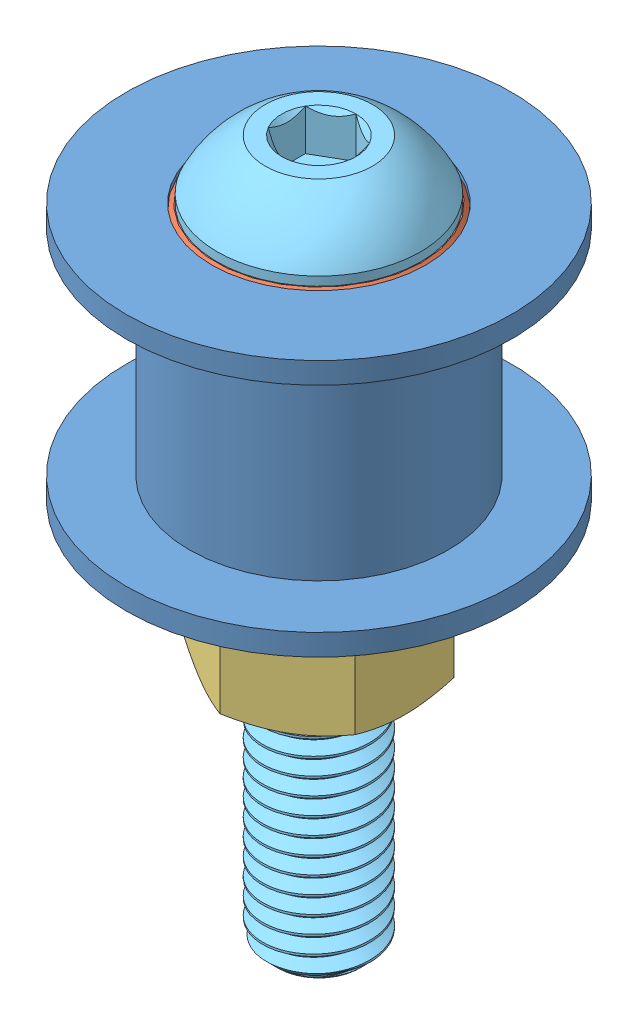
SolidWorks assembly 20T Idler Pulley wBearing, configuration Default. Lengths in mm.
Overall size (18 33.32 18).
6 component instances, 5 part files, 9 mates.
Components (placement in the parent):
- Powge 20T Idler Pulley-1: Powge 20T Idler Pulley [Default] at origin size (18 12 18)
- 7804K106_STAINLESS STEEL BALL BEARING-1: 7804K106_STAINLESS STEEL BALL BEARING [7804K106] at (0 4 0) x (1 0 0) z (0 -1 0) size (10 10 4)
- 7804K106_STAINLESS STEEL BALL BEARING-2: 7804K106_STAINLESS STEEL BALL BEARING [7804K106] at (0 -4 0) x (-1 0 0) z (0 1 0) size (10 10 4)
- 90591A146_M5 ZINC PLATED STEEL HEX NUT-1: 90591A146_M5 ZINC PLATED STEEL HEX NUT [90591A146] at (0 -10.7 0) x (1 0 0) z (0 1 0) size (8 9.24 4.46)
- 90695A037_M5 CLASS 04 STEEL THIN HEX NUT - DIN 439B-1: 90695A037_M5 CLASS 04 STEEL THIN HEX NUT - DIN 439B [90695A037] at (0 -7.35 0) size (8 3.32 9.24)
- 91239A236_M5x30 CLASS 10.9 STL BUTTON-HEAD SOCKET CAP SCREW-1: 91239A236_M5x30 CLASS 10.9 STL BUTTON-HEAD SOCKET CAP SCREW [91239A236] at (0 8.75 0) x (1 0 0) z (0 1 0) size (9.5 9.5 33.32)
Mates (geometry in assembly coordinates):
- Coincident1: coincident anti-aligned: plane of Powge 20T Idler Pulley-1 through (-5 2 0) normal (0 1 0); plane of 7804K106_STAINLESS STEEL BALL BEARING-1 through (0 2 4.8) normal (0 -1 0)
- Concentric1: concentric anti-aligned: cylinder of Powge 20T Idler Pulley-1 through (0 6 0) axis (0 1 0) radius 5; cylinder of 7804K106_STAINLESS STEEL BALL BEARING-1 through (0 2 0) axis (0 -1 0) radius 5
- Coincident2: coincident anti-aligned: plane of 90591A146_M5 ZINC PLATED STEEL HEX NUT-1 through (-4 -8.7 -2.3094) normal (0 1 0); plane of 90695A037_M5 CLASS 04 STEEL THIN HEX NUT - DIN 439B-1 through (-4 -8.7 -2.3094) normal (0 -1 0)
- Coincident3: coincident aligned: plane of 90591A146_M5 ZINC PLATED STEEL HEX NUT-1 through (0 -8.7 4.6188) normal (0.5 0 0.866025); plane of 90695A037_M5 CLASS 04 STEEL THIN HEX NUT - DIN 439B-1 through (0 -6 4.6188) normal (0.5 0 0.866025)
- Concentric2: concentric aligned: circle of 90591A146_M5 ZINC PLATED STEEL HEX NUT-1; circle of 90695A037_M5 CLASS 04 STEEL THIN HEX NUT - DIN 439B-1
- Coincident5: coincident anti-aligned: plane of 7804K106_STAINLESS STEEL BALL BEARING-2 through (0 -6 2.7) normal (0 -1 0); plane of 90695A037_M5 CLASS 04 STEEL THIN HEX NUT - DIN 439B-1 through (-4 -6 -2.3094) normal (0 1 0)
- Coincident6: coincident anti-aligned: cylinder of 7804K106_STAINLESS STEEL BALL BEARING-2 through (0 -2 0) axis (0 1 0) radius 2.5; circle of 90591A146_M5 ZINC PLATED STEEL HEX NUT-1
- Coincident7: coincident anti-aligned: plane of 7804K106_STAINLESS STEEL BALL BEARING-1 through (0 6 2.7) normal (0 1 0); plane of 91239A236_M5x30 CLASS 10.9 STL BUTTON-HEAD SOCKET CAP SCREW-1 through (0 6 4.75) normal (0 -1 0)
- Coincident8: coincident anti-aligned: cylinder of 7804K106_STAINLESS STEEL BALL BEARING-1 through (0 2 0) axis (0 -1 0) radius 2.5; circle of 91239A236_M5x30 CLASS 10.9 STL BUTTON-HEAD SOCKET CAP SCREW-1
